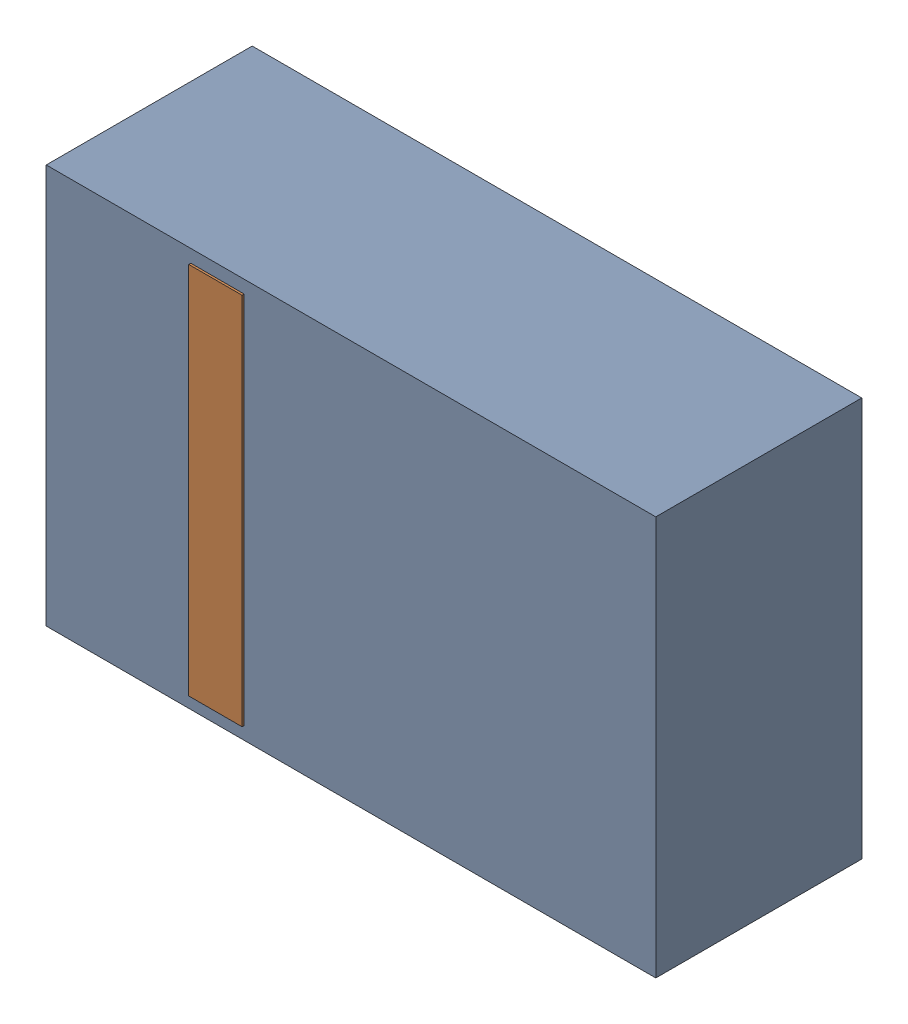
SolidWorks assembly D13, configuration Default. Lengths in mm.
Overall size (2.9 1.9 0.99).
4 component instances, 2 part files, 0 mates.
Components (placement in the parent):
- 905269392-1: 905269392 [Default] at (131.191 63.5 0) size (2.9 1.9 0.98)
  - Extruded_5-1: Extruded_5 [Default] at origin size (2.9 1.9 0.98)
- 905269800-1: 905269800 [Default] at (130.556 63.5 0.95) size (0.25 1.78 0.04)
  - Extruded_6-1: Extruded_6 [Default] at origin size (0.25 1.78 0.04)
